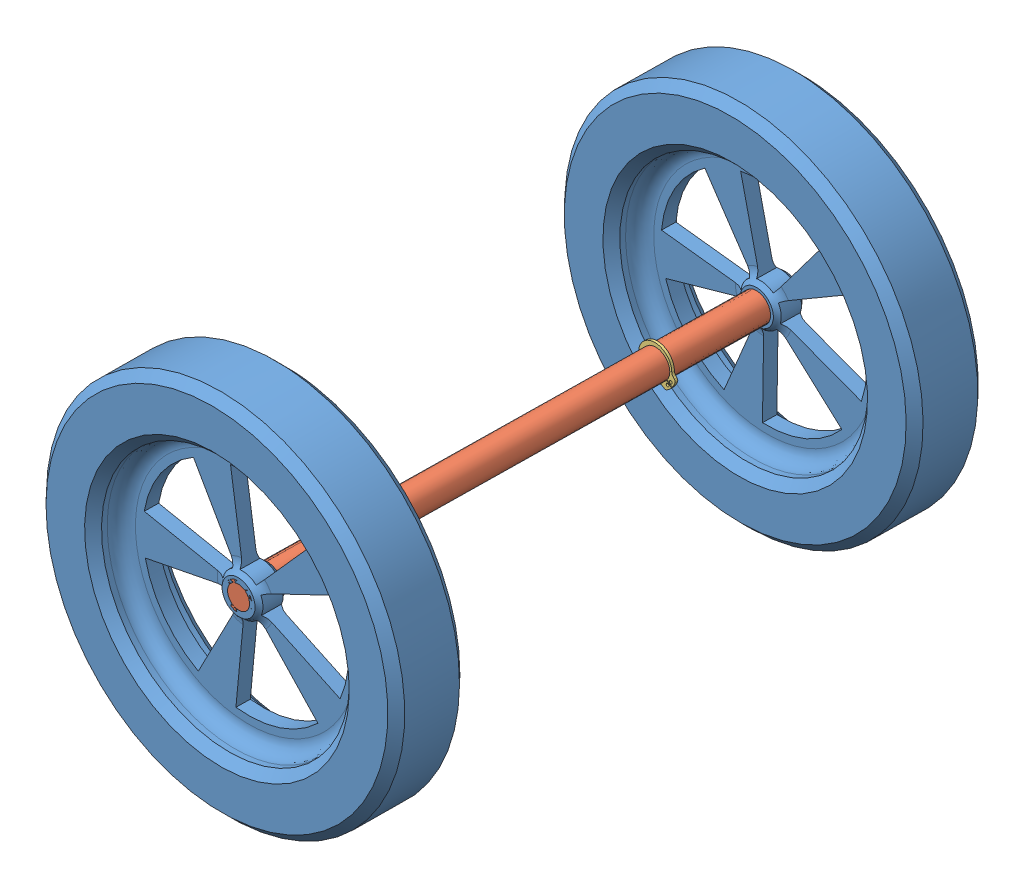
SolidWorks assembly wheel assembly, configuration Default. Lengths in mm.
Overall size (143.07 142.73 208.69).
5 component instances, 3 part files, 8 mates.
Components (placement in the parent):
- Wheel-1: Wheel [Default] at (153.0889 54.0501 242.6626) x (0.994571 -0.10193 0.020966) z (0.101773 0.994772 0.008404) size (130 25 130)
- Wheel-2: Wheel [Default] at (156.9972 55.1705 62.7085) x (0.999531 -0.021713 0.021573) z (0.021573 0.999745 0.006693) size (130 25 130)
- axle-1: axle [Default] at (157.3772 55.2794 45.213) x (0.999697 0.011491 0.021783) z (-0.021713 -0.006224 0.999745) size (10 10 190)
- heavy duty external retaining ring_am-1: heavy duty external retaining ring_am [B27.8M - 3DM1-10] at (156.4001 54.9993 90.2015) x (0.625036 0.780378 0.018433) z (-0.021713 -0.006224 0.999745) size (12.01 13.7 0.9)
- heavy duty external retaining ring_am-2: heavy duty external retaining ring_am [B27.8M - 3DM1-10] at (154.2288 54.3769 190.176) x (0.933565 -0.357955 0.018047) z (0.021713 0.006224 -0.999745) size (12.01 13.7 0.9)
Mates (geometry in assembly coordinates):
- Concentric1: concentric: cylinder of axle-1 through (153.2518 54.0968 235.1645) axis (0.021713 0.006224 -0.999745) radius 5; cylinder of heavy duty external retaining ring_am-2 through (154.2093 54.3713 191.0758) axis (0.021713 0.006224 -0.999745) radius 4.7
- Concentric2: concentric: cylinder of axle-1 through (153.2518 54.0968 235.1645) axis (0.021713 0.006224 -0.999745) radius 5; circle of heavy duty external retaining ring_am-1
- Concentric4: concentric: cylinder of Wheel-1 through (153.0889 54.0501 242.6626) axis (0.021713 0.006224 -0.999745) radius 4; cylinder of axle-1 through (153.2518 54.0968 235.1645) axis (0.021713 0.006224 -0.999745) radius 5
- Concentric5: concentric: cylinder of Wheel-2 through (156.9972 55.1705 62.7085) axis (0.021713 0.006224 -0.999745) radius 4; cylinder of axle-1 through (153.2518 54.0968 235.1645) axis (0.021713 0.006224 -0.999745) radius 5
- Coincident1: coincident: plane of Wheel-1 through (153.2518 54.0968 235.1645) normal (-0.021713 -0.006224 0.999745); plane of axle-1 through (153.2518 54.0968 235.1645) normal (-0.021713 -0.006224 0.999745)
- Coincident2: coincident: plane of Wheel-2 through (157.3772 55.2794 45.213) normal (0.021713 0.006224 -0.999745); plane of axle-1 through (157.3772 55.2794 45.213) normal (0.021713 0.006224 -0.999745)
- Distance1: distance = 35 mm: plane of heavy duty external retaining ring_am-2 through (154.2288 54.3769 190.176) normal (0.021713 0.006224 -0.999745); plane of Wheel-1 through (153.4689 54.159 225.1671) normal (0.021713 0.006224 -0.999745)
- Distance2: distance = 35 mm: plane of Wheel-2 through (157.16 55.2171 55.2104) normal (-0.021713 -0.006224 0.999745); plane of heavy duty external retaining ring_am-1 through (156.4001 54.9993 90.2015) normal (-0.021713 -0.006224 0.999745)
